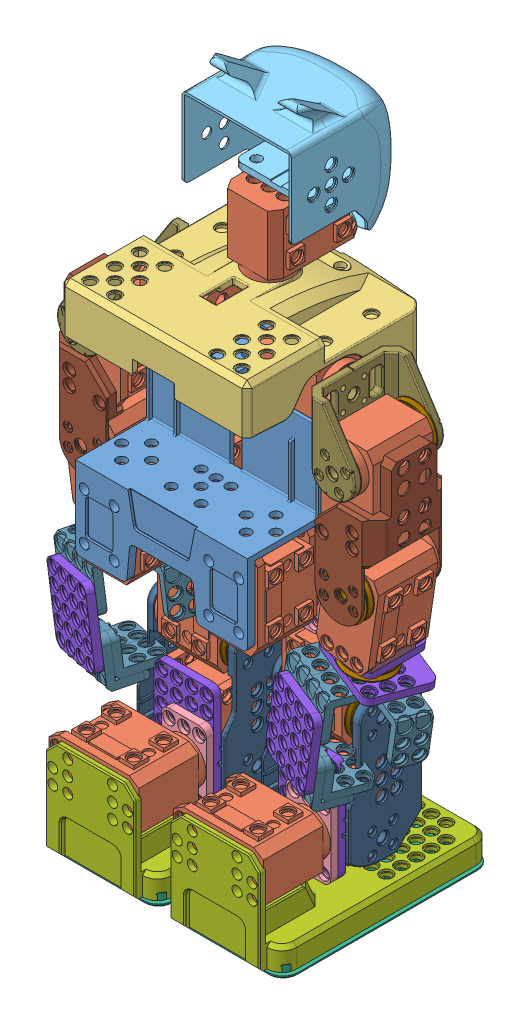
SolidWorks assembly finalAsm, configuration Default. Lengths in mm.
Overall size (144.01 272.01 92.09).
82 component instances, 14 part files, 29 mates.
Components (placement in the parent):
- bodyAsm-1: bodyAsm [Default] at origin size (77.13 106.3 74.8)
  - frm_body-1: frm_body [Default] at origin size (69 84.64 63.04)
  - XL-1: XL [Default] at (23.5 13.5 -2.0876) x (0 -1 0) z (1 0 0) size (24 36 27)
  - XL-2: XL [Default] at (-23.5 13.5 -2.0876) x (0 1 0) z (-1 0 0) size (24 36 27)
  - XL-3: XL [Default] at (-25 -47.7 27.75) x (-1 0 0) z (0 0 -1) size (24 36 27)
  - XL-4: XL [Default] at (25 -47.7 27.75) x (-1 0 0) z (0 0 -1) size (24 36 27)
  - body-1: body [Default] at (0.5 34.5 16.4124) x (-1 0 0) z (0 0 -1) size (76.25 60.08 74.8)
  - cvt-2: cvt [Default] at (-25 -56.8 12.75) x (0 1 0) z (-1 0 0) size (30 3 18)
  - cvt-3: cvt [Default] at (25 -56.8 12.75) x (0 -1 0) z (1 0 0) size (30 3 18)
- headAsm-1: headAsm [Default] at (0.5 69 -6.9327) x (-1 0 0) z (0 0 -1) size (45.91 66.53 58.75)
  - head-1: head [Default] at origin size (45.91 54.55 58.75)
  - XL-1: XL [Default] at (0 -19.5 2.4049) x (1 0 0) z (0 -1 0) size (24 36 27)
- feetAsm-1: feetAsm [Default] at (23.9 -170.9832 -0.1931) x (0 0 -1) z (1 0 0) size (87 141.68 49.5)
  - sole-1: sole [Default] at origin size (84 4.06 48)
  - foot-1: foot [Default] at (1 8.9 -1.5) x (0 0 1) z (-1 0 0) size (48 39 87)
  - XL-1: XL [Default] at (-29.9431 31 -2) x (0 -1 0) z (1 0 0) size (24 36 27)
  - cvt-1: cvt [Default] at (-14.9431 31 7.1) x (0 -1 0) z (0 0 1) size (30 3 18)
  - SPD-1: SPD [Default] at (-10.4431 37 4.1) x (0 1 0) z (0 0 1) size (42 3 24)
  - XL-2: XL [Default] at (3.0569 35 1.1) size (24 36 27)
  - wheel-1: wheel [Default] at (3.0569 25.9 -13.15) x (0 1 0) z (-1 0 0) size (19 3 19)
  - calf-1: calf [Default] at (11.7888 57.2246 1.1) x (0 0 1) z (0 -1 0) size (36 34.19 57.12)
  - XL-3: XL [Default] at (3.0569 77 1.1) x (-1 0 0) z (0 0 -1) size (24 36 27)
  - wheel-2: wheel [Default] at (3.0569 67.9 15.35) x (1 0 0) z (0 -1 0) size (19 3 19)
  - ext_02-1: ext_02 [Default] at (16.0569 87.5 1.1) x (0 0 1) z (-1 0 0) size (32 58.53 24)
  - XL-4: XL [Default] at (5.0569 118.6832 1.1) size (24 36 27)
  - SPD-2: SPD [Default] at (-8.4431 120.6832 4.1) x (0 1 0) z (0 0 1) size (42 3 24)
- feetAsm-2: feetAsm [Default] at (-26.1 -170.9832 -0.1931) x (0 0 -1) z (1 0 0) size (87 141.68 49.5)
  - sole-1: sole [Default] at origin size (84 4.06 48)
  - foot-1: foot [Default] at (1 8.9 -1.5) x (0 0 1) z (-1 0 0) size (48 39 87)
  - XL-1: XL [Default] at (-29.9431 31 -2) x (0 -1 0) z (1 0 0) size (24 36 27)
  - cvt-1: cvt [Default] at (-14.9431 31 7.1) x (0 -1 0) z (0 0 1) size (30 3 18)
  - SPD-1: SPD [Default] at (-10.4431 37 4.1) x (0 1 0) z (0 0 1) size (42 3 24)
  - XL-2: XL [Default] at (3.0569 35 1.1) size (24 36 27)
  - wheel-1: wheel [Default] at (3.0569 25.9 -13.15) x (0 1 0) z (-1 0 0) size (19 3 19)
  - calf-1: calf [Default] at (11.7888 57.2246 1.1) x (0 0 1) z (0 -1 0) size (36 34.19 57.12)
  - XL-3: XL [Default] at (3.0569 77 1.1) x (-1 0 0) z (0 0 -1) size (24 36 27)
  - wheel-2: wheel [Default] at (3.0569 67.9 15.35) x (1 0 0) z (0 -1 0) size (19 3 19)
  - ext_02-1: ext_02 [Default] at (16.0569 87.5 1.1) x (0 0 1) z (-1 0 0) size (32 58.53 24)
  - XL-4: XL [Default] at (5.0569 118.6832 1.1) size (24 36 27)
  - SPD-2: SPD [Default] at (-8.4431 120.6832 4.1) x (0 1 0) z (0 0 1) size (42 3 24)
- arm-1: arm [Default] at (63.2621 -21.1355 7.0124) x (0 0 -1) z (-1 0 0) size (36.06 93.78 29.32)
  - ext_02-1: ext_02 [Default] at origin size (32 58.53 24)
  - XL-1: XL [Default] at (0 31.086 12.3267) x (0 0.145789 -0.989316) z (1 0 0) size (24 36 27)
  - wheel-1: wheel [Default] at (-14.25 22.0832 11) x (0 -0.405591 -0.914055) z (0 0.914055 -0.405591) size (19 3 19)
  - XL-2: XL [Default] at (0 -11.5 12.5) x (0 0 1) z (-1 0 0) size (24 36 27)
  - wheel-2: wheel [Default] at (12.75 -20.6 12.5) x (0 -0.197534 -0.980296) z (0 0.980296 -0.197534) size (19 3 19)
  - frm_ext1-1: frm_ext1 [Default] at (0 -34.6355 24.7621) x (1 0 0) z (0 1 0) size (36.06 21.26 31.54)
- arm-2: arm [Default] at (-63.2621 -21.1355 7.0124) x (0 0 1) z (1 0 0) size (36.06 93.78 29.32)
  - ext_02-1: ext_02 [Default] at origin size (32 58.53 24)
  - XL-1: XL [Default] at (0 31.086 12.3267) x (0 0.145789 -0.989316) z (1 0 0) size (24 36 27)
  - wheel-1: wheel [Default] at (-14.25 22.0832 11) x (0 -0.405591 -0.914055) z (0 0.914055 -0.405591) size (19 3 19)
  - XL-2: XL [Default] at (0 -11.5 12.5) x (0 0 1) z (-1 0 0) size (24 36 27)
  - wheel-2: wheel [Default] at (12.75 -20.6 12.5) x (0 -0.197534 -0.980296) z (0 0.980296 -0.197534) size (19 3 19)
  - frm_ext1-1: frm_ext1 [Default] at (0 -34.6355 24.7621) x (1 0 0) z (0 1 0) size (36.06 21.26 31.54)
- hand-1: hand [Default] at (-47.7645 -73.7391 7.0124) x (0.989316 0.145789 0) z (0 0 1) size (46.13 57 41.49)
  - wheel-1: wheel [Default] at origin size (19 3 19)
  - square_piece-1: square_piece [Default] at (4.5 6.75 -9) x (0 0 1) z (-1 0 0) size (18 6 18)
  - l_piece-1: l_piece [Default] at (-9.142 -5.25 -5.9728) x (0 -1 0) z (-0.295919 0 0.955213) size (18 15 12)
  - l_piece-2: l_piece [Default] at (16.6488 -5.25 2.017) x (0 -1 0) z (0.295919 0 -0.955213) size (18 15 12)
  - l_piece-4: l_piece [Default] at (-11.7041 -5.25 7.3665) x (0 -1 0) z (0.955213 0 0.295919) size (18 15 12)
  - l_piece-5: l_piece [Default] at (-0.2415 -5.25 10.9175) x (0 -1 0) z (0.955213 0 0.295919) size (18 15 12)
  - l_piece-6: l_piece [Default] at (-11.7041 -47.25 7.3665) x (0 1 0) z (-0.955213 0 -0.295919) size (18 15 12)
  - l_piece-7: l_piece [Default] at (-0.2415 -47.25 10.9175) x (0 1 0) z (-0.955213 0 -0.295919) size (18 15 12)
  - l_piece-8: l_piece [Default] at (-13.0357 -36.75 11.6649) x (0.295919 0 -0.955213) z (0.955213 0 0.295919) size (18 15 12)
  - l_piece-9: l_piece [Default] at (-1.5731 -36.75 15.216) x (0.295919 0 -0.955213) z (0.955213 0 0.295919) size (18 15 12)
  - SPD-4: SPD [3B3] at (0.0005 2.25 -3) x (-1 0 -0.000151) z (0.000151 0 -1) size (18 3 24)
  - SPD-5: SPD [3B5] at (0.8878 -3.75 -2.8656) x (-0.955213 0 -0.295919) z (0.295919 0 -0.955213) size (30 3 24)
  - SPD-9: SPD [4B5] at (-8.6361 -26.25 17.7389) x (0 1 0) z (0.955213 0 0.295919) size (30 3 24)
- hand-2: hand [Default] at (47.7645 -73.7391 7.0124) x (0.989316 -0.145789 0) z (0 0 1) size (46.13 57 41.49)
  - wheel-1: wheel [Default] at origin size (19 3 19)
  - square_piece-1: square_piece [Default] at (4.5 6.75 -9) x (0 0 1) z (-1 0 0) size (18 6 18)
  - l_piece-1: l_piece [Default] at (-9.142 -5.25 -5.9728) x (0 -1 0) z (-0.295919 0 0.955213) size (18 15 12)
  - l_piece-2: l_piece [Default] at (16.6488 -5.25 2.017) x (0 -1 0) z (0.295919 0 -0.955213) size (18 15 12)
  - l_piece-4: l_piece [Default] at (-11.7041 -5.25 7.3665) x (0 -1 0) z (0.955213 0 0.295919) size (18 15 12)
  - l_piece-5: l_piece [Default] at (-0.2415 -5.25 10.9175) x (0 -1 0) z (0.955213 0 0.295919) size (18 15 12)
  - l_piece-6: l_piece [Default] at (-11.7041 -47.25 7.3665) x (0 1 0) z (-0.955213 0 -0.295919) size (18 15 12)
  - l_piece-7: l_piece [Default] at (-0.2415 -47.25 10.9175) x (0 1 0) z (-0.955213 0 -0.295919) size (18 15 12)
  - l_piece-8: l_piece [Default] at (-13.0357 -36.75 11.6649) x (0.295919 0 -0.955213) z (0.955213 0 0.295919) size (18 15 12)
  - l_piece-9: l_piece [Default] at (-1.5731 -36.75 15.216) x (0.295919 0 -0.955213) z (0.955213 0 0.295919) size (18 15 12)
  - SPD-4: SPD [3B3] at (0.0005 2.25 -3) x (-1 0 -0.000151) z (0.000151 0 -1) size (18 3 24)
  - SPD-5: SPD [3B5] at (0.8878 -3.75 -2.8656) x (-0.955213 0 -0.295919) z (0.295919 0 -0.955213) size (30 3 24)
  - SPD-9: SPD [4B5] at (-8.6361 -26.25 17.7389) x (0 1 0) z (0.955213 0 0.295919) size (30 3 24)
Mates (geometry in assembly coordinates):
- Coincident1: coincident aligned: plane of bodyAsm-1 through (0 0 0) normal (0 0 1)
- Coincident2: coincident aligned: plane of bodyAsm-1 through (0 0 0) normal (0 1 0)
- Coincident3: coincident aligned: plane of bodyAsm-1 through (0 0 0) normal (1 0 0)
- Coincident4: coordinate: point of bodyAsm-1
- Parallel1: parallel anti-aligned: plane of bodyAsm-1 through (0 0 0) normal (0 0 1); plane of headAsm-1 through (0.5 69 -6.9327) normal (0 0 -1)
- Parallel2: parallel aligned: plane of bodyAsm-1 through (0 0 0) normal (0 1 0); plane of headAsm-1 through (0.5 69 -6.9327) normal (0 1 0)
- Concentric1: concentric anti-aligned: circle of bodyAsm-1/body-1; circle of headAsm-1/XL-1
- Coincident7: coincident anti-aligned: plane of bodyAsm-1/body-1 through (0.5 34.5 -0.2376) normal (0 1 0); plane of headAsm-1/XL-1 through (0.5 34.5 -0.2376) normal (0 -1 0)
- Parallel3: parallel anti-aligned: plane of feetAsm-1 through (23.9 -170.9832 -0.1931) normal (0 0 -1)
- Parallel4: parallel aligned: plane of bodyAsm-1 through (0 0 0) normal (1 0 0); plane of feetAsm-1 through (23.9 -170.9832 -0.1931) normal (1 0 0)
- Concentric2: concentric anti-aligned: circle of bodyAsm-1/cvt-3; circle of feetAsm-1/SPD-2
- Coincident10: coincident anti-aligned: plane of bodyAsm-1/cvt-3 through (31 -68.8 9.75) normal (0 0 -1); plane of feetAsm-1/SPD-2 through (28 -50.3 9.75) normal (0 0 1)
- Parallel5: parallel anti-aligned: plane of bodyAsm-1 through (0 0 0) normal (0 0 1); plane of feetAsm-2 through (-26.1 -170.9832 -0.1931) normal (0 0 -1)
- Parallel6: parallel aligned: plane of feetAsm-2 through (-26.1 -170.9832 -0.1931) normal (1 0 0)
- Coincident13: coincident anti-aligned: circle of bodyAsm-1/cvt-2; circle of feetAsm-2/SPD-2
- Concentric10: concentric aligned: circle of bodyAsm-1/XL-1; circle of arm-1/frm_ext1-1
- Parallel12: parallel anti-aligned: plane of bodyAsm-1 through (0 0 0) normal (0 0 1); plane of arm-1 through (63.2621 -21.1355 7.0124) normal (0 0 -1)
- Parallel13: parallel anti-aligned: plane of bodyAsm-1 through (0 0 0) normal (0 1 0); plane of arm-1 through (63.2621 -21.1355 7.0124) normal (0 -1 0)
- Coincident27: coincident anti-aligned: circle of bodyAsm-1/XL-1; plane of arm-1/frm_ext1-1 through (38.5 5 -10.9876) normal (-1 0 0)
- Concentric11: concentric aligned: circle of bodyAsm-1/XL-2; circle of arm-2/frm_ext1-1
- Parallel14: parallel aligned: plane of bodyAsm-1 through (0 0 0) normal (0 0 1); plane of arm-2 through (-63.2621 -21.1355 7.0124) normal (0 0 1)
- Parallel15: parallel anti-aligned: plane of bodyAsm-1 through (0 0 0) normal (0 1 0); plane of arm-2 through (-63.2621 -21.1355 7.0124) normal (0 -1 0)
- Coincident28: coincident anti-aligned: plane of bodyAsm-1/XL-2 through (-38.5 13.5 7.0124) normal (-1 0 0); plane of arm-2/frm_ext1-1 through (-38.5 5 25.0124) normal (1 0 0)
- Concentric12: concentric anti-aligned: cylinder of hand-1/square_piece-1 through (-42.8127 -66.1865 -1.9876) axis (0 0 -1) radius 2; cylinder of arm-2/XL-1 through (-42.8127 -66.1865 16.0124) axis (0 0 1) radius 2
- Concentric13: concentric anti-aligned: cylinder of arm-2/XL-1 through (-54.6845 -67.9359 16.0124) axis (0 0 1) radius 2; cylinder of hand-1/square_piece-1 through (-54.6845 -67.9359 -1.9876) axis (0 0 -1) radius 2
- Coincident29: coincident anti-aligned: plane of arm-2/XL-1 through (-54.6845 -67.9359 16.0124) normal (0 0 -1); plane of hand-1/square_piece-1 through (-39.4074 -68.717 16.0124) normal (0 0 1)
- Concentric14: concentric aligned: cylinder of arm-1/XL-1 through (54.6845 -67.9359 16.0124) axis (0 0 1) radius 2; cylinder of hand-2/square_piece-1 through (54.6845 -67.9359 16.0124) axis (0 0 1) radius 2
- Concentric15: concentric aligned: cylinder of arm-1/XL-1 through (42.8127 -66.1865 16.0124) axis (0 0 1) radius 2; cylinder of hand-2/square_piece-1 through (42.8127 -66.1865 16.0124) axis (0 0 1) radius 2
- Coincident30: coincident anti-aligned: plane of arm-1/XL-1 through (54.6845 -67.9359 16.0124) normal (0 0 -1); plane of hand-2/square_piece-1 through (57.2151 -71.3412 16.0124) normal (0 0 1)
